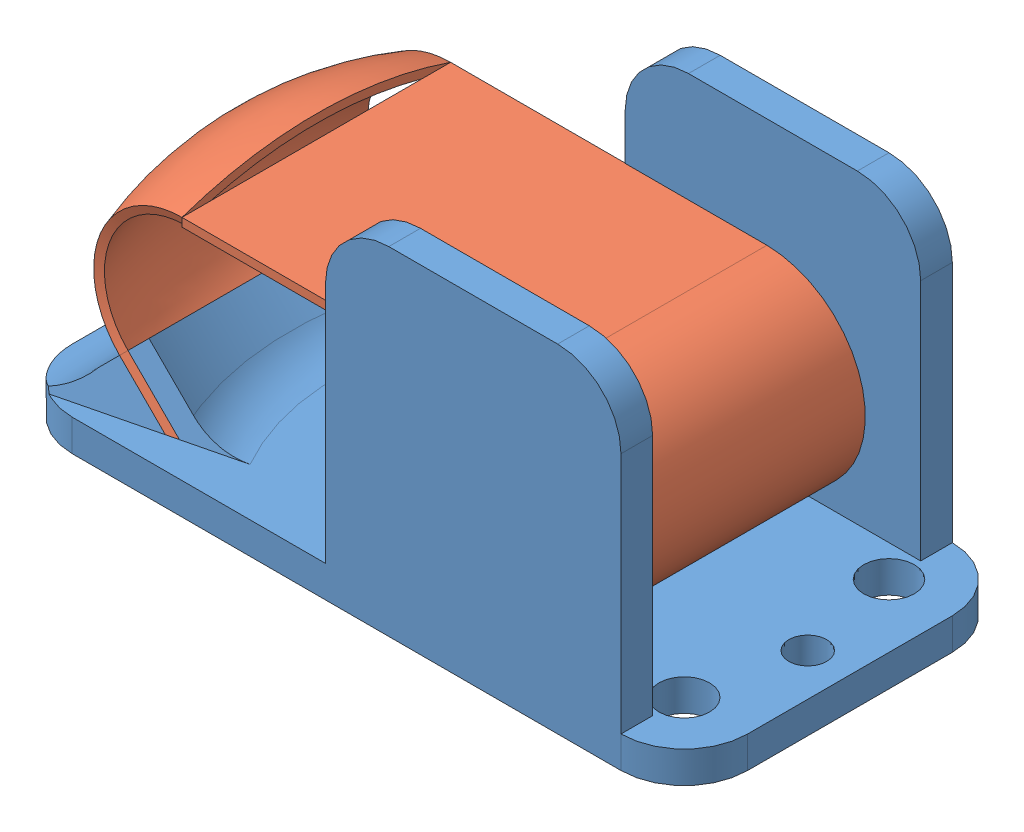
SolidWorks assembly Turnstile Rolled Antenna Definition Assembly, configuration Default. Lengths in mm.
Overall size (32.02 16 15.7).
2 component instances, 2 part files, 3 mates.
Components (placement in the parent):
- Turnstile Mount-1: Turnstile Mount [Edge Mount] at origin size (32.02 16 15.7)
- Rolled Antenna-1: Rolled Antenna [Default] at (-10.3483 0.2626 0) x (0 0 1) z (-1 0 0) size (12.74 11.62 24.94)
Mates (geometry in assembly coordinates):
- Coincident2: coincident aligned: plane of Rolled Antenna-1 through (-10.3483 0.2626 0) normal (0 0 1)
- Coincident4: coincident anti-aligned: plane of Turnstile Mount-1 through (3.4049 14.0158 0) normal (-0.707107 0.707107 0); plane of Rolled Antenna-1 through (3.4049 14.0158 0) normal (0.707107 -0.707107 0)
- Concentric3: concentric anti-aligned: cylinder of Turnstile Mount-1 through (7.8243 9.5964 0) axis (-0.707107 0.707107 0) radius 19.45; cylinder of Rolled Antenna-1 through (0.7532 16.6674 0) axis (0.707107 -0.707107 0) radius 19.45
